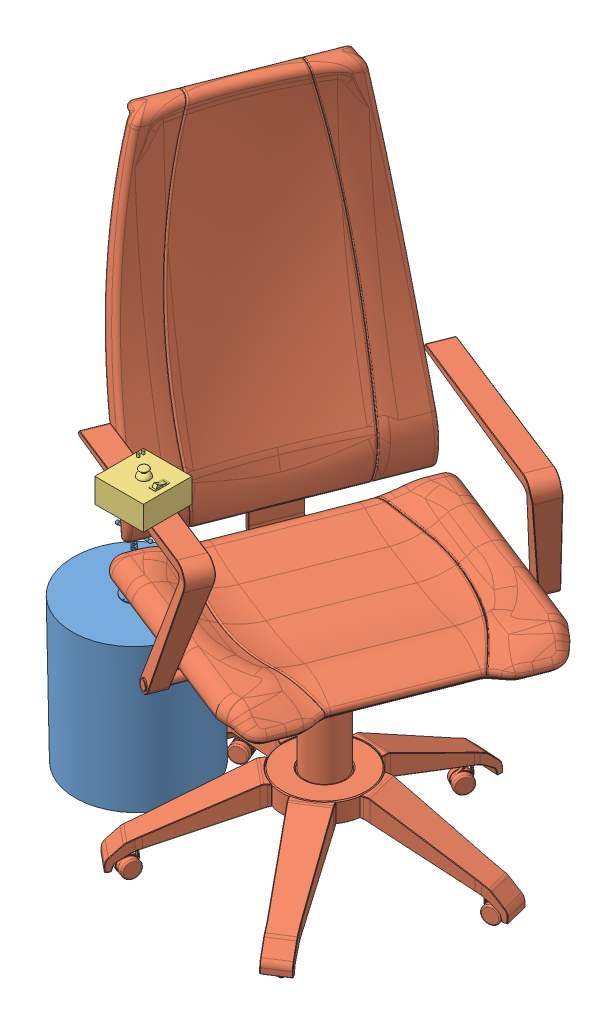
SolidWorks assembly Assem1, configuration Default. Lengths in mm.
Overall size (896.48 1245.95 856.5).
3 component instances, 3 part files, 0 mates.
Components (placement in the parent):
- attachment-part-1: attachment-part [Default] at (-219.1431 645.9762 520.2865) x (0 -0.022236 0.999753) z (-1 0 0) size (260 478.65 486.87)
- Office chair-1: Office chair [Default] at (-98.0859 720.7554 589.8414) x (0.366501 0 -0.930418) z (0.930418 0 0.366501) size (661.34 1217.24 658.04)
- controller-1: controller [Default] at (-292.3211 1422.9263 770.6149) size (100 67.28 100)
